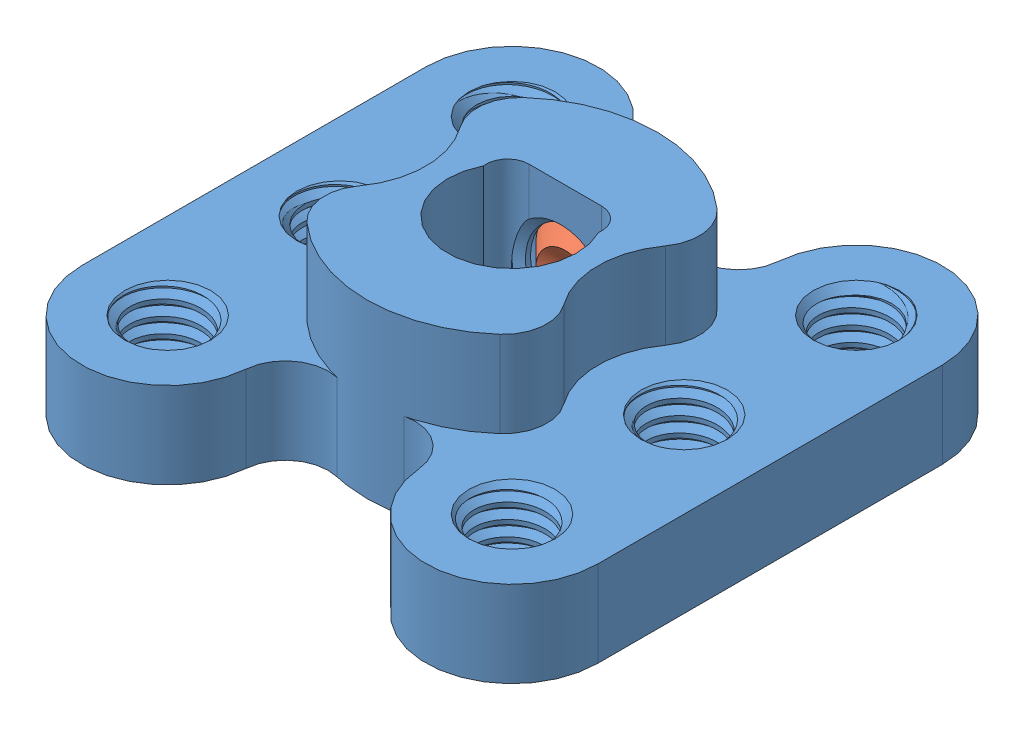
SolidWorks assembly 1308-0016-1006 assembly, configuration Default. Lengths in mm.
Overall size (24 8.14 24).
2 component instances, 2 part files, 0 mates.
Components (placement in the parent):
- 1308-0016-1006-1: 1308-0016-1006 [Default] at (6.1581 -15.9163 4.9236) size (24 8.14 24)
- 2806-0005-0004_91390A117-1: 2806-0005-0004_91390A117 [Default] at (6.1581 -11.9163 0.032) x (-0.598774 -0.800918 0) z (0 0 -1) size (5.13 5 4.14)
